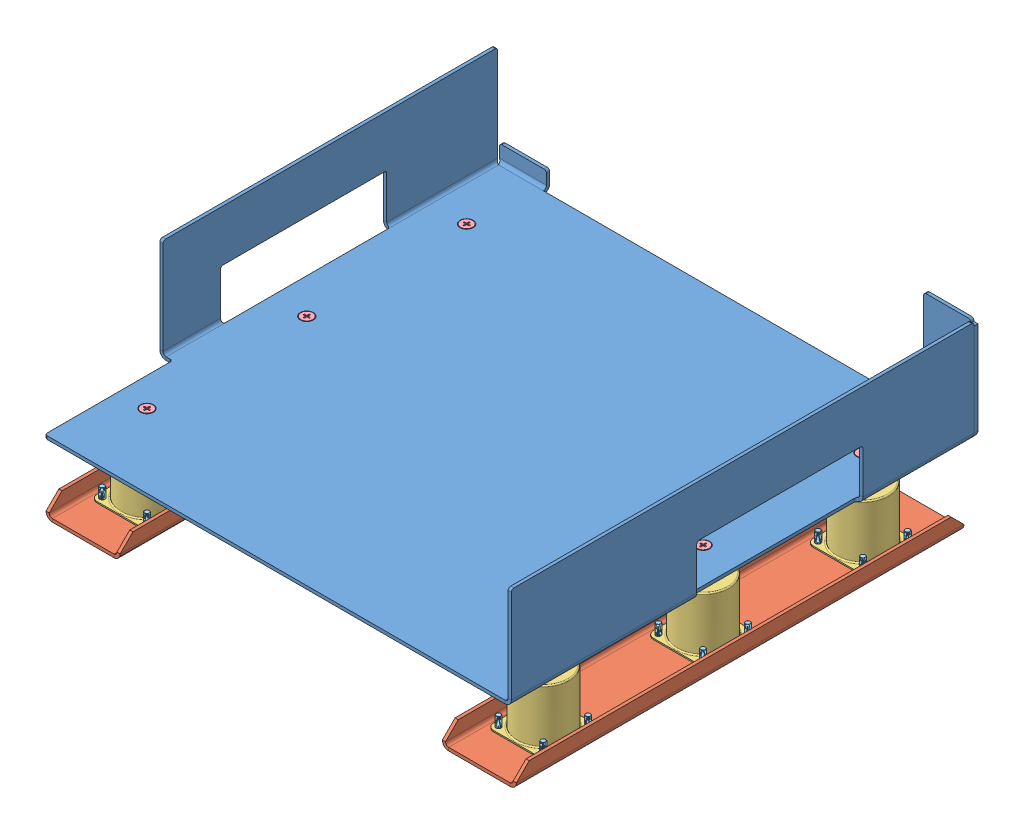
SolidWorks assembly Сборка, configuration По умолчанию. Lengths in mm.
Overall size (375.45 141.9 365.44).
39 component instances, 5 part files, 56 mates.
Components (placement in the parent):
- 1_Полка-1: 1_Полка [По умолчанию<Как обработанный>] at (-182.6691 43.1061 558.1681) size (375.45 80.44 365.44)
- 2_Основание-1: 2_Основание [По умолчанию] at (-150.1691 -18.3939 375.6681) x (0 0 -1) z (1 0 0) size (350 15 58)
- 2_Основание-2: 2_Основание [По умолчанию] at (159.8309 -18.3939 375.6681) x (0 0 1) z (-1 0 0) size (350 15 58)
- 8_Амортизатор-1: 8_Амортизатор [По умолчанию] at (-150.1691 -17.3939 500.6681) size (44 59 44)
- 8_Амортизатор-2: 8_Амортизатор [По умолчанию] at (-150.1691 -17.3939 375.6681) size (44 59 44)
- 8_Амортизатор-3: 8_Амортизатор [По умолчанию] at (159.8309 -17.3939 375.6681) size (44 59 44)
- 8_Амортизатор-4: 8_Амортизатор [По умолчанию] at (159.8309 -17.3939 250.6681) size (44 59 44)
- 8_Амортизатор-5: 8_Амортизатор [По умолчанию] at (159.8309 -17.3939 500.6681) size (44 59 44)
- 8_Амортизатор-6: 8_Амортизатор [По умолчанию] at (-150.1691 -17.3939 250.6681) size (44 59 44)
- 7_Винт_М5-1: 7_Винт_М5 [По умолчанию] at (159.8309 31.2061 250.6681) size (9.3 12.3 9.3)
- 7_Винт_М5-2: 7_Винт_М5 [По умолчанию] at (159.8309 31.2061 500.6681) size (9.3 12.3 9.3)
- 7_Винт_М5-3: 7_Винт_М5 [По умолчанию] at (159.8309 31.2061 375.6681) size (9.3 12.3 9.3)
- 7_Винт_М5-4: 7_Винт_М5 [По умолчанию] at (-150.1691 31.2061 500.6681) size (9.3 12.3 9.3)
- 7_Винт_М5-5: 7_Винт_М5 [По умолчанию] at (-150.1691 31.2061 375.6681) size (9.3 12.3 9.3)
- 7_Винт_М5-6: 7_Винт_М5 [По умолчанию] at (-150.1691 31.2061 250.6681) size (9.3 12.3 9.3)
- 6_Винт_М4-1: 6_Винт_М4 [По умолчанию] at (-132.6691 -9.2939 358.1681) x (1 0 0) z (0 0 -1) size (8.4 12.23 8.4)
- 6_Винт_М4-2: 6_Винт_М4 [По умолчанию] at (-132.6691 -9.2939 393.1681) x (1 0 0) z (0 0 -1) size (8.4 12.23 8.4)
- 6_Винт_М4-3: 6_Винт_М4 [По умолчанию] at (-132.6691 -9.2939 268.1681) x (1 0 0) z (0 0 -1) size (8.4 12.23 8.4)
- 6_Винт_М4-4: 6_Винт_М4 [По умолчанию] at (-132.6691 -9.2939 233.1681) x (1 0 0) z (0 0 -1) size (8.4 12.23 8.4)
- 6_Винт_М4-5: 6_Винт_М4 [По умолчанию] at (-167.6691 -9.2939 268.1681) x (1 0 0) z (0 0 -1) size (8.4 12.23 8.4)
- 6_Винт_М4-6: 6_Винт_М4 [По умолчанию] at (-167.6691 -9.2939 233.1681) x (1 0 0) z (0 0 -1) size (8.4 12.23 8.4)
- 6_Винт_М4-7: 6_Винт_М4 [По умолчанию] at (-167.6691 -9.2939 358.1681) x (1 0 0) z (0 0 -1) size (8.4 12.23 8.4)
- 6_Винт_М4-8: 6_Винт_М4 [По умолчанию] at (-167.6691 -9.2939 393.1681) x (1 0 0) z (0 0 -1) size (8.4 12.23 8.4)
- 6_Винт_М4-9: 6_Винт_М4 [По умолчанию] at (-132.6691 -9.2939 483.1681) x (1 0 0) z (0 0 -1) size (8.4 12.23 8.4)
- 6_Винт_М4-10: 6_Винт_М4 [По умолчанию] at (-167.6691 -9.2939 483.1681) x (1 0 0) z (0 0 -1) size (8.4 12.23 8.4)
- 6_Винт_М4-11: 6_Винт_М4 [По умолчанию] at (-132.6691 -9.2939 518.1681) x (1 0 0) z (0 0 -1) size (8.4 12.23 8.4)
- 6_Винт_М4-12: 6_Винт_М4 [По умолчанию] at (-167.6691 -9.2939 518.1681) x (1 0 0) z (0 0 -1) size (8.4 12.23 8.4)
- 6_Винт_М4-13: 6_Винт_М4 [По умолчанию] at (142.3309 -9.2939 393.1681) x (1 0 0) z (0 0 -1) size (8.4 12.23 8.4)
- 6_Винт_М4-14: 6_Винт_М4 [По умолчанию] at (177.3309 -9.2939 393.1681) x (1 0 0) z (0 0 -1) size (8.4 12.23 8.4)
- 6_Винт_М4-15: 6_Винт_М4 [По умолчанию] at (142.3309 -9.2939 358.1681) x (1 0 0) z (0 0 -1) size (8.4 12.23 8.4)
- 6_Винт_М4-16: 6_Винт_М4 [По умолчанию] at (177.3309 -9.2939 358.1681) x (1 0 0) z (0 0 -1) size (8.4 12.23 8.4)
- 6_Винт_М4-17: 6_Винт_М4 [По умолчанию] at (142.3309 -9.2939 268.1681) x (1 0 0) z (0 0 -1) size (8.4 12.23 8.4)
- 6_Винт_М4-18: 6_Винт_М4 [По умолчанию] at (177.3309 -9.2939 233.1681) x (1 0 0) z (0 0 -1) size (8.4 12.23 8.4)
- 6_Винт_М4-19: 6_Винт_М4 [По умолчанию] at (142.3309 -9.2939 233.1681) x (1 0 0) z (0 0 -1) size (8.4 12.23 8.4)
- 6_Винт_М4-20: 6_Винт_М4 [По умолчанию] at (177.3309 -9.2939 268.1681) x (1 0 0) z (0 0 -1) size (8.4 12.23 8.4)
- 6_Винт_М4-21: 6_Винт_М4 [По умолчанию] at (142.3309 -9.2939 483.1681) x (1 0 0) z (0 0 -1) size (8.4 12.23 8.4)
- 6_Винт_М4-22: 6_Винт_М4 [По умолчанию] at (142.3309 -9.2939 518.1681) x (1 0 0) z (0 0 -1) size (8.4 12.23 8.4)
- 6_Винт_М4-23: 6_Винт_М4 [По умолчанию] at (177.3309 -9.2939 518.1681) x (1 0 0) z (0 0 -1) size (8.4 12.23 8.4)
- 6_Винт_М4-24: 6_Винт_М4 [По умолчанию] at (177.3309 -9.2939 483.1681) x (1 0 0) z (0 0 -1) size (8.4 12.23 8.4)
Mates (geometry in assembly coordinates):
- Концентричный1: concentric aligned: circle of 1_Полка-1; circle of 8_Амортизатор-6
- Совпадение2: coincident anti-aligned: plane of 1_Полка-1 through (-182.6691 40.6061 558.1681) normal (0 -1 0); plane of 8_Амортизатор-6 through (-150.1691 40.6061 250.6681) normal (0 1 0)
- Совпадение3: coincident aligned: cone of 1_Полка-1 through (-150.1691 40.7561 250.6681) axis (0 -1 0); cone of 7_Винт_М5-6 through (-150.1691 42.6561 250.6681) axis (0 -1 0)
- Концентричный2: concentric aligned: circle of 1_Полка-1; circle of 8_Амортизатор-2
- Совпадение4: coincident anti-aligned: plane of 1_Полка-1 through (-182.6691 40.6061 558.1681) normal (0 -1 0); plane of 8_Амортизатор-2 through (-150.1691 40.6061 375.6681) normal (0 1 0)
- Концентричный3: concentric aligned: circle of 1_Полка-1; circle of 8_Амортизатор-1
- Совпадение5: coincident anti-aligned: plane of 1_Полка-1 through (-182.6691 40.6061 558.1681) normal (0 -1 0); plane of 8_Амортизатор-1 through (-150.2735 37.2511 500.3923) normal (0 1 0)
- Концентричный4: concentric aligned: circle of 1_Полка-1; circle of 8_Амортизатор-4
- Совпадение6: coincident anti-aligned: plane of 1_Полка-1 through (-182.6691 40.6061 558.1681) normal (0 -1 0); plane of 8_Амортизатор-4 through (159.809 39.8994 250.679) normal (0 1 0)
- Концентричный5: concentric aligned: circle of 1_Полка-1; circle of 8_Амортизатор-3
- Совпадение7: coincident anti-aligned: plane of 1_Полка-1 through (-182.6691 40.6061 558.1681) normal (0 -1 0); plane of 8_Амортизатор-3 through (159.8309 40.6061 375.6681) normal (0 1 0)
- Концентричный6: concentric aligned: circle of 1_Полка-1; circle of 8_Амортизатор-5
- Совпадение8: coincident anti-aligned: plane of 1_Полка-1 through (-182.6691 40.6061 558.1681) normal (0 -1 0); plane of 8_Амортизатор-5 through (159.8309 40.6061 500.6681) normal (0 1 0)
- Совпадение9: coincident aligned: cone of 1_Полка-1 through (-150.1691 40.7561 375.6681) axis (0 -1 0); cone of 7_Винт_М5-5 through (-150.1691 42.6561 375.6681) axis (0 -1 0)
- Совпадение10: coincident aligned: cone of 1_Полка-1 through (-150.1691 40.7561 500.6681) axis (0 -1 0); cone of 7_Винт_М5-4 through (-150.1691 42.6561 500.6681) axis (0 -1 0)
- Совпадение11: coincident aligned: cone of 1_Полка-1 through (159.8309 40.7561 500.6681) axis (0 -1 0); cone of 7_Винт_М5-2 through (159.8309 42.6561 500.6681) axis (0 -1 0)
- Совпадение12: coincident aligned: cone of 1_Полка-1 through (159.8309 40.7561 375.6681) axis (0 -1 0); cone of 7_Винт_М5-3 through (159.8309 42.6561 375.6681) axis (0 -1 0)
- Совпадение14: coincident aligned: cone of 1_Полка-1 through (159.8309 40.7561 250.6681) axis (0 -1 0); cone of 7_Винт_М5-1 through (159.8309 42.6561 250.6681) axis (0 -1 0)
- Концентричный11: concentric: circle of 2_Основание-1; circle of 8_Амортизатор-6
- Концентричный12: concentric: circle of 2_Основание-1; circle of 8_Амортизатор-6
- Концентричный13: concentric: circle of 2_Основание-1; circle of 8_Амортизатор-2
- Концентричный14: concentric: cylinder of 2_Основание-1; cylinder of 8_Амортизатор-2 through (-132.6691 24.8061 393.1681) axis (0 -1 0) radius 2
- Концентричный15: concentric: circle of 2_Основание-1; cylinder of 8_Амортизатор-1 through (-167.6691 24.8061 483.1681) axis (0 -1 0) radius 2
- Концентричный16: concentric: circle of 2_Основание-1; circle of 8_Амортизатор-1
- Совпадение15: coincident anti-aligned: plane of 2_Основание-1 through (-150.1691 -18.3939 375.6681) normal (0 1 0); plane of 8_Амортизатор-1 through (-150.1691 -18.3939 500.6681) normal (0 -1 0)
- Совпадение16: coincident aligned: cone of 2_Основание-1 through (-167.6691 -20.8939 518.1681) axis (0 1 0); cone of 6_Винт_М4-12 through (-167.6691 -20.7939 518.1681) axis (0 1 0)
- Совпадение17: coincident aligned: cone of 2_Основание-1 through (-132.6691 -20.8939 518.1681) axis (0 1 0); cone of 6_Винт_М4-11 through (-132.6691 -20.7939 518.1681) axis (0 1 0)
- Совпадение18: coincident anti-aligned: cone of 2_Основание-1 through (-167.6691 -20.8939 483.1681) axis (0 1 0); circle of 6_Винт_М4-10
- Совпадение19: coincident anti-aligned: cone of 2_Основание-1 through (-132.6691 -20.8939 483.1681) axis (0 1 0); circle of 6_Винт_М4-9
- Совпадение20: coincident aligned: cone of 2_Основание-1 through (-167.6691 -20.8939 393.1681) axis (0 1 0); cone of 6_Винт_М4-8 through (-167.6691 -20.7939 393.1681) axis (0 1 0)
- Совпадение21: coincident aligned: cone of 2_Основание-1 through (-132.6691 -20.8939 358.1681) axis (0 1 0); cone of 6_Винт_М4-1 through (-132.6691 -20.7939 358.1681) axis (0 1 0)
- Совпадение22: coincident aligned: cone of 2_Основание-1 through (-167.6691 -20.8939 358.1681) axis (0 1 0); cone of 6_Винт_М4-7 through (-167.6691 -20.7939 358.1681) axis (0 1 0)
- Совпадение23: coincident aligned: cone of 2_Основание-1 through (-132.6691 -20.8939 393.1681) axis (0 1 0); cone of 6_Винт_М4-2 through (-132.6691 -20.7939 393.1681) axis (0 1 0)
- Совпадение24: coincident aligned: cone of 2_Основание-1 through (-167.6691 -20.8939 268.1681) axis (0 1 0); cone of 6_Винт_М4-5 through (-167.6691 -20.7939 268.1681) axis (0 1 0)
- Совпадение25: coincident aligned: cone of 2_Основание-1 through (-167.6691 -20.8939 233.1681) axis (0 1 0); cone of 6_Винт_М4-6 through (-167.6691 -20.7939 233.1681) axis (0 1 0)
- Совпадение26: coincident aligned: cone of 2_Основание-1 through (-132.6691 -20.8939 233.1681) axis (0 1 0); cone of 6_Винт_М4-4 through (-132.6691 -20.7939 233.1681) axis (0 1 0)
- Совпадение27: coincident aligned: cone of 2_Основание-1 through (-132.6691 -20.8939 268.1681) axis (0 1 0); cone of 6_Винт_М4-3 through (-132.6691 -20.7939 268.1681) axis (0 1 0)
- Концентричный17: concentric: circle of 2_Основание-2; cylinder of 8_Амортизатор-5 through (142.3309 24.8061 483.1681) axis (0 -1 0) radius 2
- Концентричный18: concentric: circle of 2_Основание-2; cylinder of 8_Амортизатор-5 through (177.3309 24.8061 518.1681) axis (0 -1 0) radius 2
- Концентричный19: concentric: circle of 2_Основание-2; cylinder of 8_Амортизатор-3 through (142.3309 24.8061 393.1681) axis (0 -1 0) radius 2
- Концентричный20: concentric: circle of 2_Основание-2; circle of 8_Амортизатор-3
- Концентричный21: concentric: circle of 2_Основание-2; cylinder of 8_Амортизатор-4 through (142.3309 24.8061 268.1681) axis (0 -1 0) radius 2
- Концентричный22: concentric: circle of 2_Основание-2; cylinder of 8_Амортизатор-4 through (177.3309 24.8061 233.1681) axis (0 -1 0) radius 2
- Совпадение28: coincident anti-aligned: plane of 2_Основание-2 through (159.8309 -18.3939 375.6681) normal (0 1 0); plane of 8_Амортизатор-5 through (159.8309 -18.3939 500.6681) normal (0 -1 0)
- Совпадение29: coincident aligned: cone of 2_Основание-2 through (142.3309 -20.8939 518.1681) axis (0 1 0); cone of 6_Винт_М4-22 through (142.3309 -20.7939 518.1681) axis (0 1 0)
- Совпадение30: coincident aligned: cone of 2_Основание-2 through (177.3309 -20.8939 518.1681) axis (0 1 0); cone of 6_Винт_М4-23 through (177.3309 -20.7939 518.1681) axis (0 1 0)
- Совпадение31: coincident aligned: cone of 2_Основание-2 through (142.3309 -20.8939 483.1681) axis (0 1 0); cone of 6_Винт_М4-21 through (142.3309 -20.7939 483.1681) axis (0 1 0)
- Совпадение32: coincident aligned: cone of 2_Основание-2 through (177.3309 -20.8939 483.1681) axis (0 1 0); cone of 6_Винт_М4-24 through (177.3309 -20.7939 483.1681) axis (0 1 0)
- Совпадение33: coincident aligned: cone of 2_Основание-2 through (142.3309 -20.8939 393.1681) axis (0 1 0); cone of 6_Винт_М4-13 through (142.3309 -20.7939 393.1681) axis (0 1 0)
- Совпадение34: coincident aligned: cone of 2_Основание-2 through (177.3309 -20.8939 393.1681) axis (0 1 0); cone of 6_Винт_М4-14 through (177.3309 -20.7939 393.1681) axis (0 1 0)
- Совпадение35: coincident aligned: cone of 2_Основание-2 through (142.3309 -20.8939 358.1681) axis (0 1 0); cone of 6_Винт_М4-15 through (142.3309 -20.7939 358.1681) axis (0 1 0)
- Совпадение36: coincident aligned: cone of 2_Основание-2 through (177.3309 -20.8939 358.1681) axis (0 1 0); cone of 6_Винт_М4-16 through (177.3309 -20.7939 358.1681) axis (0 1 0)
- Совпадение37: coincident aligned: cone of 2_Основание-2 through (142.3309 -20.8939 268.1681) axis (0 1 0); cone of 6_Винт_М4-17 through (142.3309 -20.7939 268.1681) axis (0 1 0)
- Совпадение38: coincident aligned: cone of 2_Основание-2 through (177.3309 -20.8939 233.1681) axis (0 1 0); cone of 6_Винт_М4-18 through (177.3309 -20.7939 233.1681) axis (0 1 0)
- Совпадение39: coincident aligned: cone of 2_Основание-2 through (177.3309 -20.8939 268.1681) axis (0 1 0); cone of 6_Винт_М4-20 through (177.3309 -20.7939 268.1681) axis (0 1 0)
- Совпадение40: coincident aligned: cone of 2_Основание-2 through (142.3309 -20.8939 233.1681) axis (0 1 0); cone of 6_Винт_М4-19 through (142.3309 -20.7939 233.1681) axis (0 1 0)
